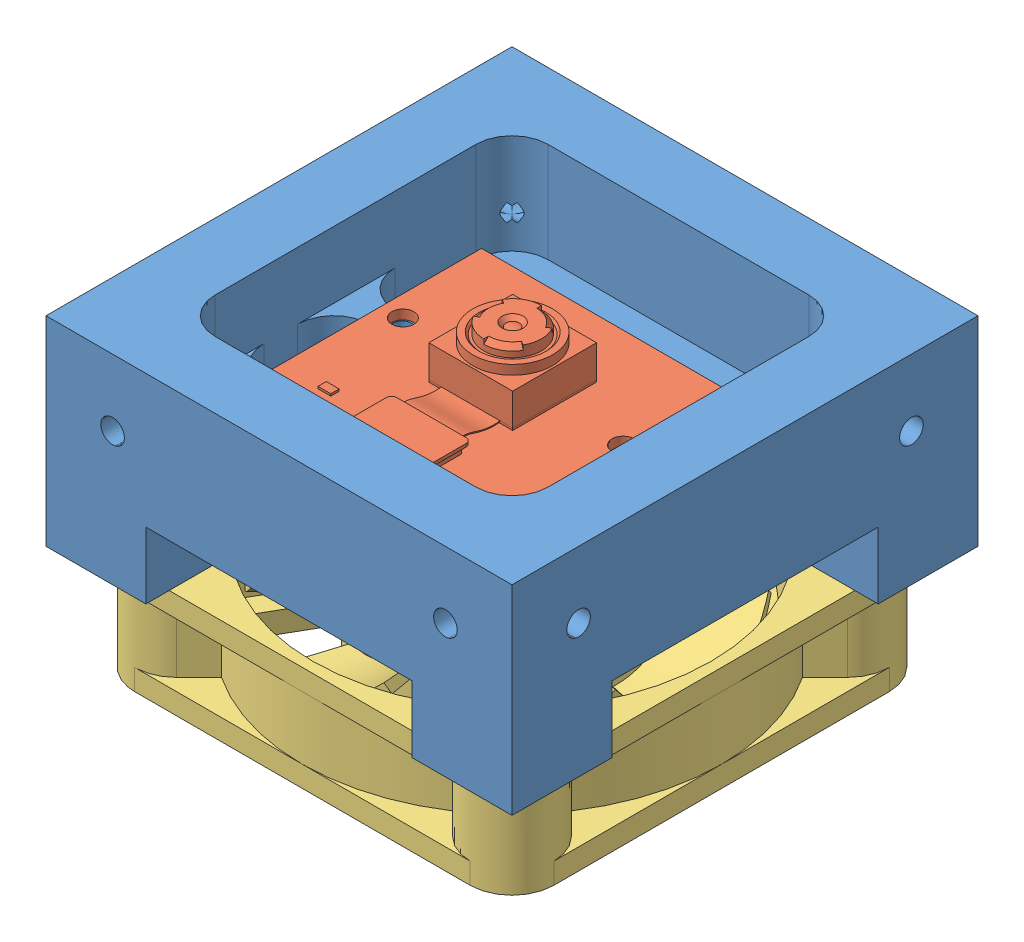
SolidWorks assembly Camera Assembly, configuration Default. Lengths in mm.
Overall size (44.45 29.05 44.45).
3 component instances, 3 part files, 9 mates.
Components (placement in the parent):
- Camera Plate-1: Camera Plate [Default] at (0 -10.5 0) size (44.45 19.05 44.45)
- RasPi_Camera-1: RasPi_Camera [Default] at (0.0315 -2.6983 -0.0586) size (25 8.25 24)
- 1939K170_DC EQUIPMENT COOLING FAN-1: 1939K170_DC EQUIPMENT COOLING FAN [Default] at (0 -26.85 0) x (1 0 0) z (0 1 0) size (40 40 10.64)
Mates (geometry in assembly coordinates):
- Coincident1: coincident anti-aligned: plane of Camera Plate-1 through (10.5315 -4.15 -0.0586) normal (0 1 0); plane of RasPi_Camera-1 through (0.0315 -4.15 -0.0586) normal (0 -1 0)
- Concentric1: concentric anti-aligned: cylinder of Camera Plate-1 through (10.5315 -4.15 -0.0586) axis (0 -1 0) radius 0.889; cylinder of RasPi_Camera-1 through (10.5315 -4.15 -0.0586) axis (0 1 0) radius 1.05
- Concentric2: concentric anti-aligned: cylinder of Camera Plate-1 through (10.5315 -4.15 12.4414) axis (0 -1 0) radius 0.889; cylinder of RasPi_Camera-1 through (10.5315 -4.15 12.4414) axis (0 1 0) radius 1.05
- Coincident2: coincident aligned: plane of RasPi_Camera-1 through (0.063 0 0) normal (0 1 0); plane of assembly through (0 0 0) normal (0 1 0)
- Coincident3: coincident aligned: plane of Camera Plate-1 through (0 -10.5 0) normal (1 0 0); plane of assembly through (0 0 0) normal (1 0 0)
- Coincident4: coincident aligned: plane of Camera Plate-1 through (0 -10.5 0) normal (0 0 1); plane of assembly through (0 0 0) normal (0 0 1)
- Coincident5: coincident anti-aligned: plane of Camera Plate-1 through (0 -16.85 0) normal (0 -1 0); plane of 1939K170_DC EQUIPMENT COOLING FAN-1 through (0 -16.85 0) normal (0 1 0)
- Concentric3: concentric aligned: cylinder of Camera Plate-1 through (-16 -16.85 -16) axis (0 -1 0) radius 1.1303; cylinder of 1939K170_DC EQUIPMENT COOLING FAN-1 through (-16 -16.85 -16) axis (0 -1 0) radius 1.778
- Concentric4: concentric aligned: cylinder of Camera Plate-1 through (-16 -16.85 16) axis (0 -1 0) radius 1.1303; cylinder of 1939K170_DC EQUIPMENT COOLING FAN-1 through (-16 -16.85 16) axis (0 -1 0) radius 1.778
